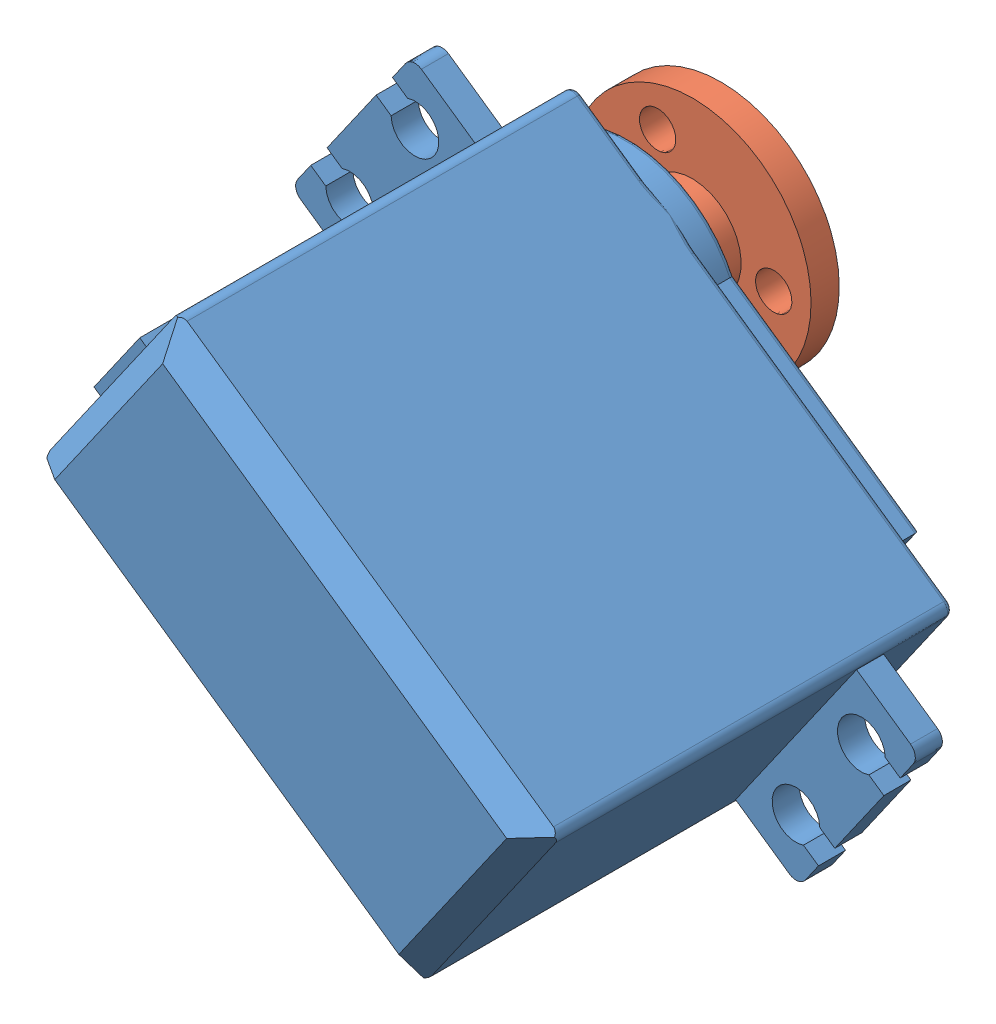
SolidWorks assembly MG996R_Coupler_Assembly, configuration Default. Lengths in mm.
Overall size (54.6 45.62 47.69).
2 component instances, 2 part files, 2 mates.
Components (placement in the parent):
- GrippeR_Arm_Servo_MG996R-1: GrippeR_Arm_Servo_MG996R [Default] at (-101.0329 -4.3314 31.0456) size (54.6 45.62 44.38)
- Servo_Coupler-1: Servo_Coupler [Default] at (5.1419 40.4291 16.2282) x (0.908925 0.416925 -0.005486) z (0.004069 0.004289 0.999983) size (21 21 21.42)
Mates (geometry in assembly coordinates):
- Concentric1: concentric: cylinder of assembly; axis of GrippeR_Arm_Servo_MG996R-1 through (5.1996 40.4898 30.3938) axis (-0.004069 -0.004289 -0.999983); cylinder of Servo_Coupler-1 through (5.1651 40.4535 21.9281) axis (-0.004069 -0.004289 -0.999983) radius 1.525
- Distance1: distance = 0.5 mm anti-aligned: plane of GrippeR_Arm_Servo_MG996R-1 through (5.1671 40.4557 22.4281) normal (-0.004069 -0.004289 -0.999983); plane of Servo_Coupler-1 through (5.1651 40.4535 21.9281) normal (0.004069 0.004289 0.999983)
